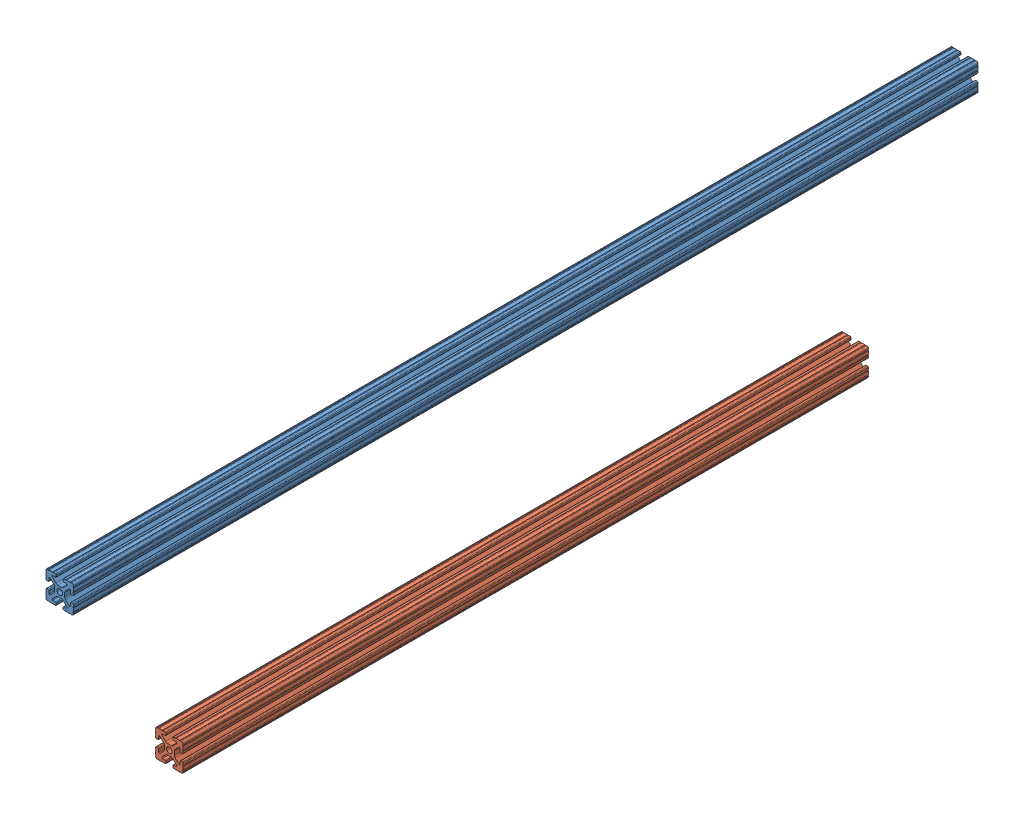
SolidWorks assembly Drive Station Side with T-Slot, configuration Default. Lengths in mm.
Overall size (25.4 203.2 838.2).
2 component instances, 2 part files, 0 mates.
Components (placement in the parent):
- Modifiable T-Slot Bar (33 in)-1: Modifiable T-Slot Bar (33 in) [Default] at (22.4388 294.0274 200.7009) x (0 0 1) z (-1 0 0) size (838.2 25.4 25.4)
- Modifiable T-Slot Bar (25 in)-1: Modifiable T-Slot Bar (25 in) [Default] at (-71.4513 116.2274 637.1834) x (0 0 -1) z (1 0 0) size (635 25.4 25.4)
